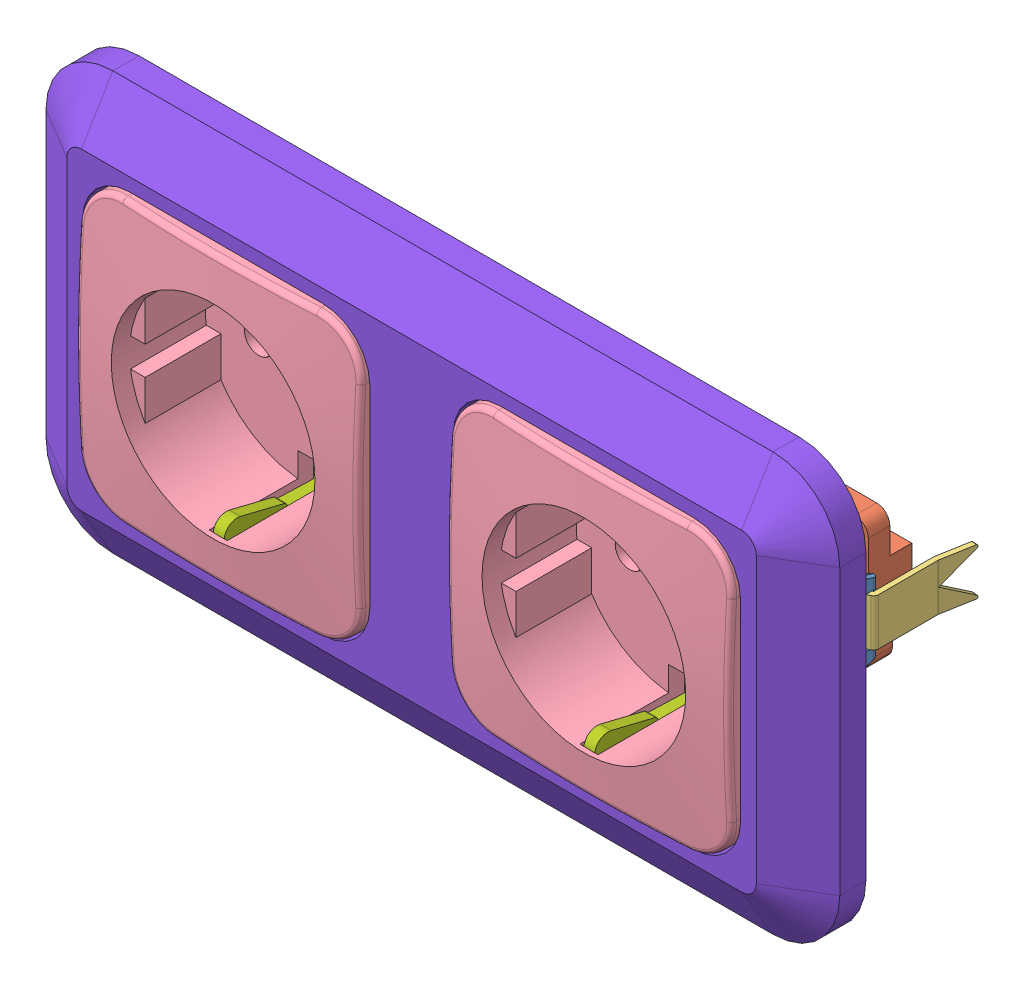
SolidWorks assembly Steckdose_2er, configuration Standard. Lengths in mm.
Overall size (152 80 49.07).
19 component instances, 8 part files, 6 mates.
Components (placement in the parent):
- Steckdose-1: Steckdose [Standard] at (57.8004 107.6649 -6.8552) x (1 0 0) z (0 -1 0) size (71 49.07 71)
  - Montageplatte.02-1: Montageplatte.02 [Standard] at (-76.9981 11 50.9191) x (1 0 0) z (0 1 0) size (71 71 18.97)
  - Halter-1: Halter [Standard] at (-76.9981 11 50.9191) x (1 0 0) z (0 1 0) size (45.97 31.9 15.37)
  - Kralle.04-1: Kralle.04 [Standard] at (-74.3121 12.4168 50.9191) x (0.996195 -0.087156 0) z (0.087156 0.996195 0) size (8.78 9 23.36)
  - Kralle.04-2: Kralle.04 [Standard] at (74.3121 12.4168 -50.9191) x (-0.996195 -0.087156 0) z (-0.087156 0.996195 0) size (8.78 9 23.36)
  - Buchse-1: Buchse [Standard] at (-76.9981 11 50.9191) x (1 0 0) z (0 1 0) size (64.03 64.03 27)
  - Stromklemme_1.02-1: Stromklemme_1.02 [Standard] at (-76.9981 11 50.7921) x (1 0 0) z (0 1 0) size (8.38 19.82 12.51)
  - Stromklemme_2.02-1: Stromklemme_2.02 [Standard] at (-76.9981 11 50.7921) x (1 0 0) z (0 1 0) size (8.38 19.82 12.51)
  - Erdleiter-1: Erdleiter [Standard] at (-76.9981 11 50.9191) x (1 0 0) z (0 1 0) size (7.24 44.01 27.12)
- Steckdose-2: Steckdose [Standard] at (128.8004 107.6649 -6.8552) x (1 0 0) z (0 -1 0) size (71 49.07 71)
  - Montageplatte.02-1: Montageplatte.02 [Standard] at (-76.9981 11 50.9191) x (1 0 0) z (0 1 0) size (71 71 18.97)
  - Halter-1: Halter [Standard] at (-76.9981 11 50.9191) x (1 0 0) z (0 1 0) size (45.97 31.9 15.37)
  - Kralle.04-1: Kralle.04 [Standard] at (-74.3121 12.4168 50.9191) x (0.996195 -0.087156 0) z (0.087156 0.996195 0) size (8.78 9 23.36)
  - Kralle.04-2: Kralle.04 [Standard] at (74.3121 12.4168 -50.9191) x (-0.996195 -0.087156 0) z (-0.087156 0.996195 0) size (8.78 9 23.36)
  - Buchse-1: Buchse [Standard] at (-76.9981 11 50.9191) x (1 0 0) z (0 1 0) size (64.03 64.03 27)
  - Stromklemme_1.02-1: Stromklemme_1.02 [Standard] at (-76.9981 11 50.7921) x (1 0 0) z (0 1 0) size (8.38 19.82 12.51)
  - Stromklemme_2.02-1: Stromklemme_2.02 [Standard] at (-76.9981 11 50.7921) x (1 0 0) z (0 1 0) size (8.38 19.82 12.51)
  - Erdleiter-1: Erdleiter [Standard] at (-76.9981 11 50.9191) x (1 0 0) z (0 1 0) size (7.24 44.01 27.12)
- Wandplatte-1: Wandplatte [2er] at (17.3004 67.6649 4.1448) size (152 80 11)
Mates (geometry in assembly coordinates):
- Deckungsgleich1: coincident anti-aligned: plane of Steckdose-2/Buchse-1 through (128.8004 81.1649 -1.8552) normal (0 0 -1); plane of Wandplatte-1 through (110.3004 89.1649 -1.8552) normal (0 0 1)
- Deckungsgleich2: coincident anti-aligned: plane of Steckdose-1/Buchse-1 through (57.8004 81.1649 -1.8552) normal (0 0 -1); plane of Wandplatte-1 through (39.3004 89.1649 -1.8552) normal (0 0 1)
- Abstand1: distance = 0.5 mm anti-aligned: plane of Wandplatte-1 through (39.3004 135.1649 -1.8552) normal (0 -1 0); plane of Steckdose-1/Buchse-1 through (39.3004 134.6649 -1.8552) normal (0 1 0)
- Abstand2: distance = 0.5 mm anti-aligned: plane of Steckdose-1/Buchse-1 through (30.8004 89.1649 -1.8552) normal (-1 0 0); plane of Wandplatte-1 through (30.3004 126.1649 -1.8552) normal (1 0 0)
- Abstand3: distance = 0.5 mm anti-aligned: plane of Steckdose-2/Buchse-1 through (110.3004 134.6649 -1.8552) normal (0 1 0); plane of Wandplatte-1 through (110.3004 135.1649 -1.8552) normal (0 -1 0)
- Abstand4: distance = 0.5 mm anti-aligned: plane of Steckdose-2/Buchse-1 through (101.8004 89.1649 -1.8552) normal (-1 0 0); plane of Wandplatte-1 through (101.3004 126.1649 -1.8552) normal (1 0 0)
